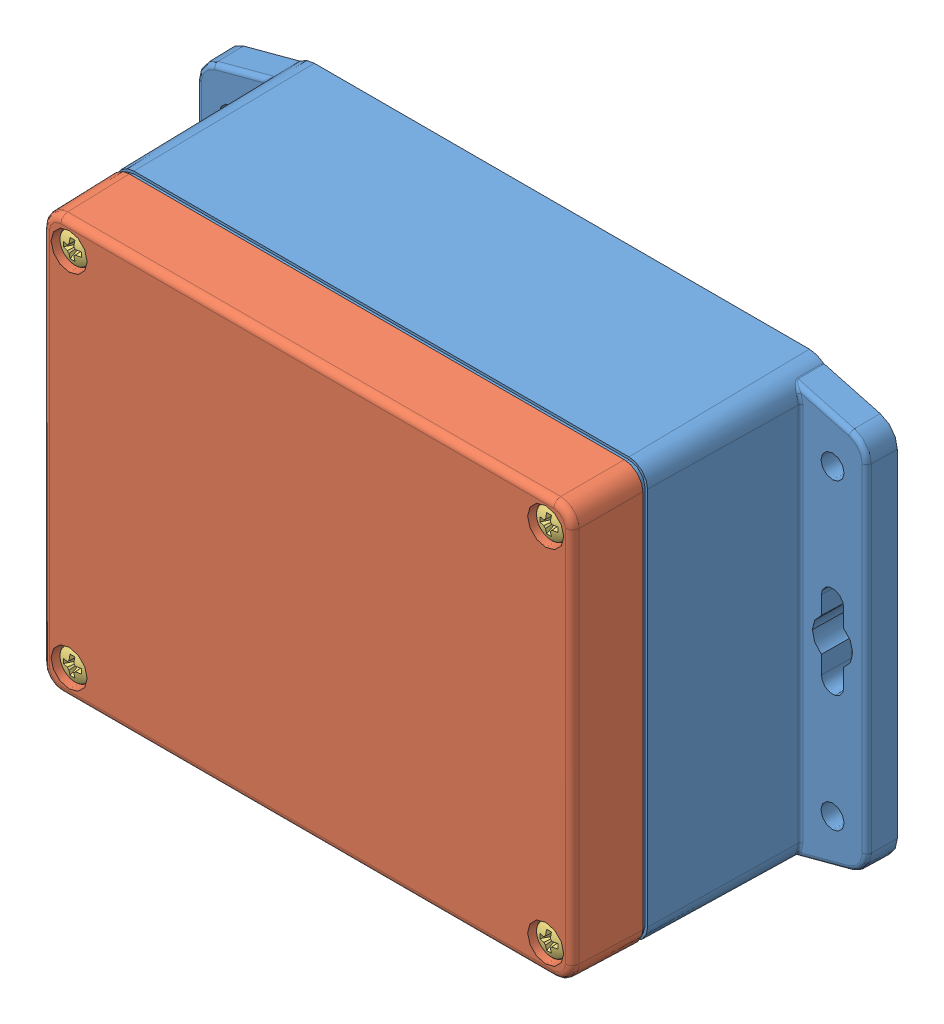
SolidWorks assembly Gainta G311MF Enclosure, configuration По умолчанию. Lengths in mm.
Overall size (145 91.4 55).
6 component instances, 3 part files, 6 mates.
Components (placement in the parent):
- Gainta G311MF - base-1: Gainta G311MF - base [Default] at origin size (145 91.4 41.5)
- Gainta G311MF - cover-1: Gainta G311MF - cover [Default] at (0 0 40) size (115 90 15)
- Pan head screw - M4x16-3: Pan head screw - M4x16 [M4 x 16] at (51.5 -39 54.6) x (0 0 -1) z (1 0 0) size (19.02 6.8 6.8)
- Pan head screw - M4x16-7: Pan head screw - M4x16 [M4 x 16] at (-51.5 -39 54.6) x (0 0 -1) z (1 0 0) size (19.02 6.8 6.8)
- Pan head screw - M4x16-8: Pan head screw - M4x16 [M4 x 16] at (51.5 39 54.6) x (0 0 -1) z (1 0 0) size (19.02 6.8 6.8)
- Pan head screw - M4x16-9: Pan head screw - M4x16 [M4 x 16] at (-51.5 39 54.6) x (0 0 -1) z (1 0 0) size (19.02 6.8 6.8)
Mates (geometry in assembly coordinates):
- Совпадение1: coincident anti-aligned: plane of Gainta G311MF - base-1 through (57 -44.5 40) normal (0 0 1); plane of Gainta G311MF - cover-1 through (-57.5 -45 40) normal (0 0 -1)
- Концентричный1: concentric aligned: cylinder of Gainta G311MF - base-1 through (-51.5 39 25) axis (0 0 1) radius 1.65; cylinder of Gainta G311MF - cover-1 through (-51.5 39 51.5) axis (0 0 1) radius 3.9
- Концентричный2: concentric anti-aligned: cylinder of Gainta G311MF - base-1 through (51.5 -39 25) axis (0 0 1) radius 1.65; cylinder of Gainta G311MF - cover-1 through (51.5 -39 51.5) axis (0 0 -1) radius 2.25
- Концентричный3: concentric anti-aligned: cylinder of Gainta G311MF - cover-1 through (51.5 -39 51.5) axis (0 0 -1) radius 2.25; cylinder of Pan head screw - M4x16-3 through (51.5 -39 80) axis (0 0 1) radius 2
- Совпадение2: coincident anti-aligned: plane of Gainta G311MF - cover-1 through (47.6 -42.9788 51.5) normal (0 0 1); plane of Pan head screw - M4x16-3 through (51.5 -37 51.5) normal (0 0 -1)
- Параллельность1: parallel: line of Gainta G311MF - cover-1 through (53.2645 -44.7639 53.5262) axis (-1 0 0); plane of Pan head screw - M4x16-3 through (53.65 -38.485 54.6) normal (0 -1 0)
